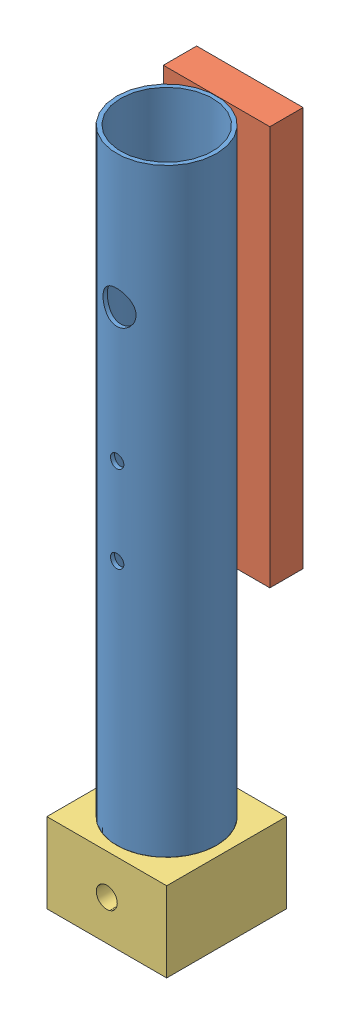
SolidWorks assembly test assembly, configuration Default. Lengths in mm.
Overall size (90 510 107.5).
3 component instances, 3 part files, 5 mates.
Components (placement in the parent):
- cylinder(1)-2: cylinder(1) [Default] at (1495.4914 60 -115.6233) x (0 0 -1) z (1 0 0) size (75 450 75)
- second-1: second [Default] at (1455.4914 210 -178.1233) x (-1 0 0) z (0 0 -1) size (80 300 25)
- first-1: first [Default] at (1450.4914 0 -115.6233) size (90 60 90)
Mates (geometry in assembly coordinates):
- Concentric1: concentric anti-aligned: cylinder of cylinder(1)-2 through (1495.4914 245 -153.1233) axis (0 0 1) radius 5; cylinder of second-1 through (1495.4914 245 -153.1233) axis (0 0 -1) radius 5
- Tangent1: tangent anti-aligned: cylinder of cylinder(1)-2 through (1495.4914 60 -115.6233) axis (0 -1 0) radius 37.5; plane of second-1 through (1455.4914 210 -153.1233) normal (0 0 1)
- Concentric3: concentric anti-aligned: cylinder of cylinder(1)-2 through (1495.4914 410 -153.1233) axis (0 0 1) radius 12.4; cylinder of second-1 through (1495.4914 410 -153.1233) axis (0 0 -1) radius 12.4
- Coincident3: coincident anti-aligned: circle of cylinder(1)-2; circle of first-1
- Coincident4: coincident anti-aligned: plane of first-1 through (1540.4914 0 -70.6233) normal (0 -1 0); plane of assembly through (0 0 0) normal (0 1 0)
